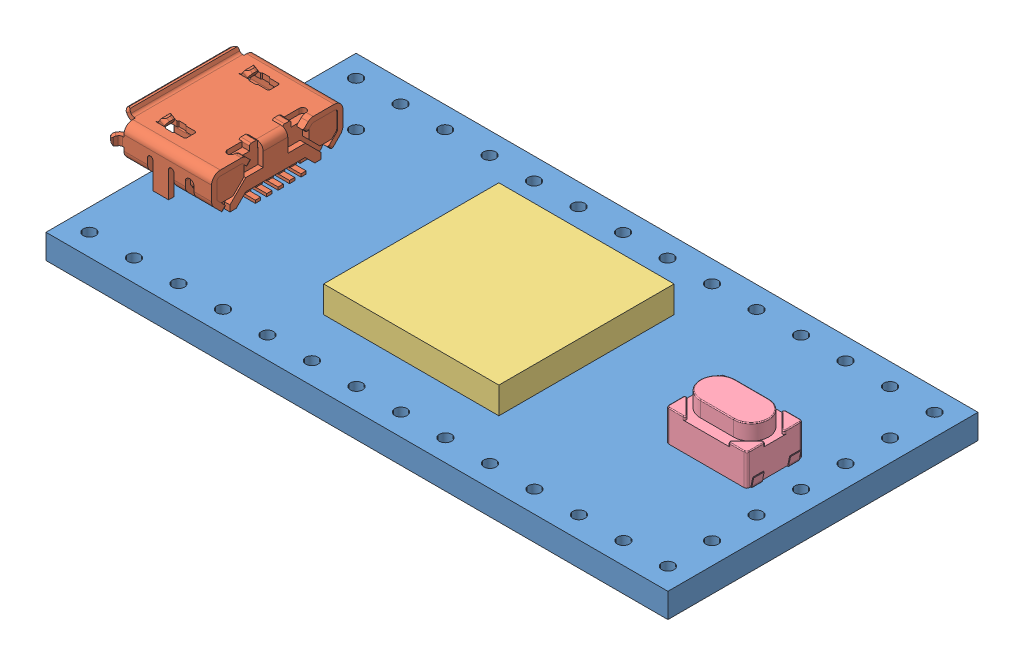
SolidWorks assembly Teensy_4.0_Assembly, configuration Default. Lengths in mm.
Overall size (36.75 4.12 17.7).
4 component instances, 4 part files, 10 mates.
Components (placement in the parent):
- Teensy_4.0_PCB-1: Teensy_4.0_PCB [Default] at (-32.9666 11.0804 9.3926) size (35.5 1.4 17.7)
- Micro USB-B Female 5Pin SMD-1: Micro USB-B Female 5Pin SMD [Default] at (-46.3666 13.7054 9.3926) x (0 0 1) z (0 1 0) size (8.05 5.8 3.73)
- NXP iMXRT1062-1: NXP iMXRT1062 [Default] at (-33.7166 12.4804 9.3926) x (0 0 1) z (-1 0 0) size (10 1.52 10)
- SKRPACE010 v4-1: SKRPACE010 v4 [Default] at (-22.5666 12.5304 7.7926) size (4.89 2.55 3.2)
Mates (geometry in assembly coordinates):
- Coincident1: coincident anti-aligned: plane of Teensy_4.0_PCB-1 through (-32.9666 12.4804 9.3926) normal (0 1 0); plane of Micro USB-B Female 5Pin SMD-1 through (-51.3666 12.4804 6.7755) normal (0 -1 0)
- Parallel1: parallel aligned: plane of Micro USB-B Female 5Pin SMD-1 through (-46.4666 14.6304 10.0926) normal (1 0 0)
- Coincident3: coincident aligned: plane of Teensy_4.0_PCB-1 through (-32.9666 11.0804 9.3926) normal (0 0 1); plane of Micro USB-B Female 5Pin SMD-1 through (-46.3666 13.7054 9.3926) normal (0 0 1)
- Distance1: distance = 1 mm aligned: plane of Micro USB-B Female 5Pin SMD-1 through (-49.7166 13.9804 5.3926) normal (-1 0 0); plane of Teensy_4.0_PCB-1 through (-50.7166 12.4804 0.5426) normal (-1 0 0)
- Coincident5: coincident anti-aligned: plane of Teensy_4.0_PCB-1 through (-32.9666 12.4804 9.3926) normal (0 1 0); plane of NXP iMXRT1062-1 through (-33.7166 12.4804 9.3926) normal (0 -1 0)
- Distance2: distance = 13.5 mm aligned: plane of NXP iMXRT1062-1 through (-28.7166 14.0004 4.3926) normal (1 0 0); plane of Teensy_4.0_PCB-1 through (-15.2166 12.4804 0.5426) normal (1 0 0)
- Coincident7: coincident aligned: plane of Teensy_4.0_PCB-1 through (-32.9666 11.0804 9.3926) normal (0 0 1); plane of NXP iMXRT1062-1 through (-33.7166 12.4804 9.3926) normal (0 0 1)
- Coincident8: coincident anti-aligned: plane of Teensy_4.0_PCB-1 through (-32.9666 12.4804 9.3926) normal (0 1 0); plane of SKRPACE010 v4-1 through (-18.2666 12.4804 8.3426) normal (0 -1 0)
- Coincident10: coincident aligned: plane of Teensy_4.0_PCB-1 through (-32.9666 11.0804 9.3926) normal (0 0 1); plane of SKRPACE010 v4-1 through (-22.5666 12.5304 9.3926) normal (0 0 1)
- Distance3: distance = 2.75 mm aligned: plane of Teensy_4.0_PCB-1 through (-15.2166 12.4804 0.5426) normal (1 0 0); plane of SKRPACE010 v4-1 through (-17.9666 12.5304 10.9926) normal (1 0 0)
